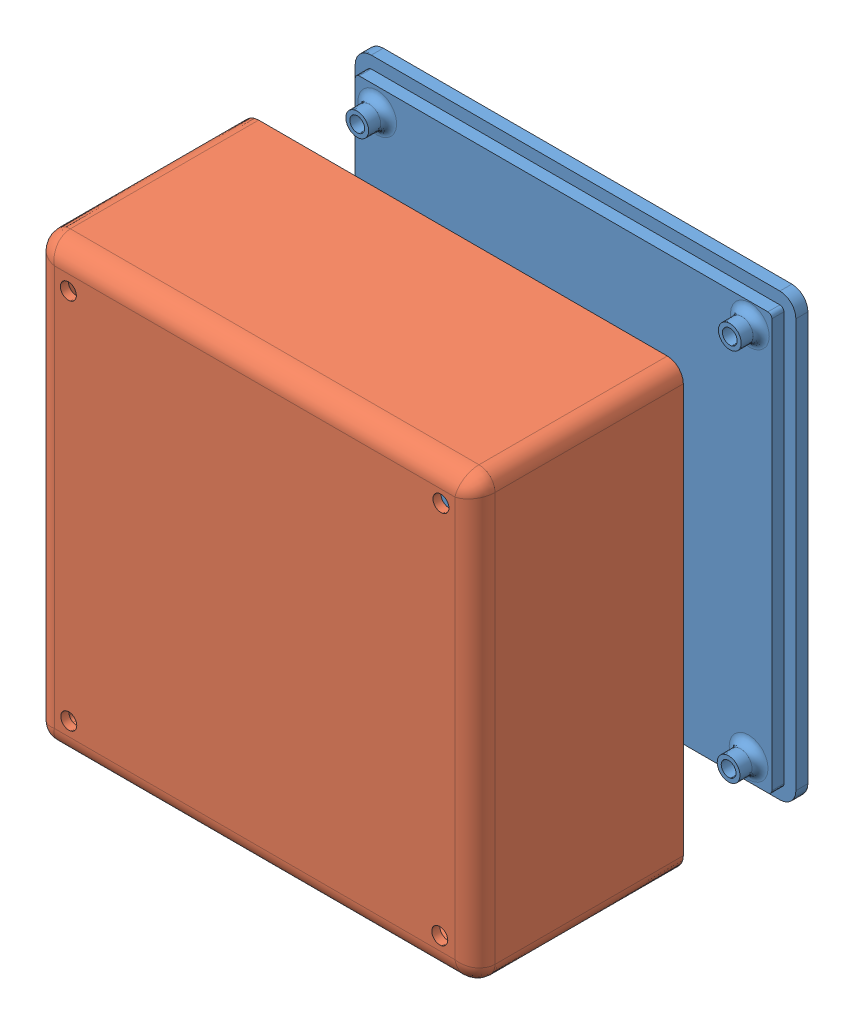
SolidWorks assembly Emsamble de base y tapa, configuration Predeterminado. Lengths in mm.
Overall size (110 110 83.1).
2 component instances, 2 part files, 2 mates.
Components (placement in the parent):
- 01_Base 124x107.7x6mm-1: 01_Base 124x107.7x6mm [Predeterminado] at (-5.9586 0.3192 124.1) size (110 110 11)
- 02_tapa-1: 02_tapa [Predeterminado] at (-5.9586 0.3192 155.1973) size (110 110 52)
Mates (geometry in assembly coordinates):
- Coincidente1: coincident anti-aligned: plane of 01_Base 124x107.7x6mm-1 through (-57.9586 52.3192 130.1) normal (0 1 0); plane of 02_tapa-1 through (-57.9586 52.3192 242.3359) normal (0 -1 0)
- Concéntrica1: concentric anti-aligned: cylinder of 01_Base 124x107.7x6mm-1 through (45.0414 51.3192 130.1) axis (0 0 -1) radius 1; cylinder of 02_tapa-1 through (45.0414 51.3192 242.3359) axis (0 0 1) radius 1
